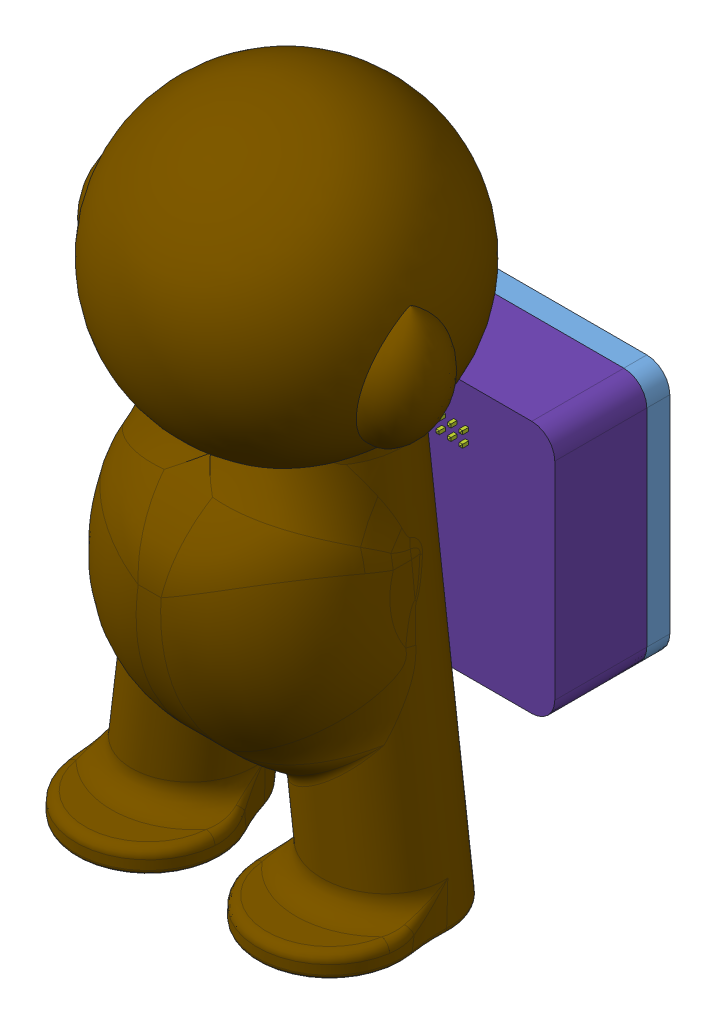
SolidWorks assembly Assieme, configuration Default. Lengths in mm.
Overall size (76.35 143.32 85.77).
234 component instances, 55 part files, 10 mates.
Components (placement in the parent):
- board_assembly v3.step-1: board_assembly v3.step [Default] at (-30.2543 4.1644 104.9326) size (50.34 46.95 25.99)
  - arduino nano.step-1: arduino nano.step [Default] at (25.6471 31.2311 -53.379) x (0 -1 0) z (-1 0 0) size (45 18.6 18)
    - MINIUSB - MEASURED.step-1: MINIUSB - MEASURED.step [Default] at (38.98 1.65 -7.62) x (0 0 1) z (-1 0 0) size (10.9 4.8 10.4)
      - MINIUSBSHELL.step-1: MINIUSBSHELL.step [Default] at origin size (10.9 3.75 9.4)
      - MINIUSBCORE.step-1: MINIUSBCORE.step [Default] at (0 0 6.7) x (-1 0 0) z (0 0 -1) size (7.7 4.5 8.2)
      - MINI USB CONTACT.step-1: MINI USB CONTACT.step [Default] at (-1.6 0 5.7) x (-1 0 0) z (0 0 -1) size (0.51 2.55 9.4)
      - MINI USB CONTACT.step-2: MINI USB CONTACT.step [Default] at (-0.8 0 5.7) x (-1 0 0) z (0 0 -1) size (0.51 2.55 9.4)
      - MINI USB CONTACT.step-3: MINI USB CONTACT.step [Default] at (0 0 5.7) x (-1 0 0) z (0 0 -1) size (0.51 2.55 9.4)
      - MINI USB CONTACT.step-4: MINI USB CONTACT.step [Default] at (0.8 0 5.7) x (-1 0 0) z (0 0 -1) size (0.51 2.55 9.4)
      - MINI USB CONTACT.step-5: MINI USB CONTACT.step [Default] at (1.6 0 5.7) x (-1 0 0) z (0 0 -1) size (0.51 2.55 9.4)
    - reset button.step-1: reset button.step [Default] at (15.25 1.6 -8.05) x (0 0 -1) z (1 0 0) size (5.2 2.15 3)
      - reset core.step-1: reset core.step [Default] at origin size (5.2 2.15 2.8)
      - reset shell.step-1: reset shell.step [Default] at (0 1.65 0) x (0 0 1) z (-1 0 0) size (3 1.65 4)
    - nano-board.step-1: nano-board.step [Default] at origin size (43.2 4.6 18)
    - 2pin_header__02.step-1: 2pin_header__02.step [Default] at (-1.143 1.6 -7.62) size (5 11.75 2.54)
    - 2pin_header__02.step-2: 2pin_header__02.step [Default] at (-1.143 1.6 -5.08) size (5 11.75 2.54)
    - 2pin_header__02.step-3: 2pin_header__02.step [Default] at (-1.143 1.6 -10.16) size (5 11.75 2.54)
    - 15pin_header__.step-1: 15pin_header__.step [Default] x (0 0 1) z (1 0 0) size (2.54 11.75 38.1)
    - 15pin_header__.step-2: 15pin_header__.step [Default] at (0 0 -15.24) x (0 0 1) z (1 0 0) size (2.54 11.75 38.1)
    - atmega328.step-1: atmega328.step [Default] at (23.85 1.75 -7.62) x (-0.707107 0 0.707107) z (-0.707107 0 -0.707107) size (10 1.1 10)
    - ftdi FT232rl.step-1: ftdi FT232rl.step [Default] at (29.05 0 -7.67) x (0 0 -1) z (-1 0 0) size (9.25 1.9 10.2)
    - smt_resistor222.step-1: smt_resistor222.step [Default] at (21.86 0 -5.8) x (0 0 -1) z (-1 0 0) size (1.7 0.6 3.8)
    - smt_resistor222.step-2: smt_resistor222.step [Default] at (21.86 0 -9) x (0 0 -1) z (-1 0 0) size (1.7 0.6 3.8)
    - smt_resistor222.step-3: smt_resistor222.step [Default] at (36.75 0 -7.6) x (0 0 -1) z (-1 0 0) size (1.7 0.6 3.8)
    - smt_resistor222.step-4: smt_resistor222.step [Default] at (36.75 0 -12) x (0 0 -1) z (-1 0 0) size (1.7 0.6 3.8)
    - smt_resistor222.step-5: smt_resistor222.step [Default] at (8.2 0 -2.6) x (0 0 -1) z (-1 0 0) size (1.7 0.6 3.8)
    - led.step-1: led.step [Default] at (10.4 1.6 -2.8) size (4 0.85 1.47)
    - led.step-2: led.step [Default] at (10.4 1.6 -5.55) size (4 0.85 1.47)
    - led.step-3: led.step [Default] at (10.4 1.6 -12.5) size (4 0.85 1.47)
    - led.step-4: led.step [Default] at (10.4 1.6 -9.05) size (4 0.85 1.47)
    - 16mhz crystal - measured.step-1: 16mhz crystal - measured.step [Default] at (18.5113 1.6 -3.5541) x (0.707107 0 0.707107) z (-0.707107 0 0.707107) size (3.4 0.8 2)
    - cap106C.step-1: cap106C.step [Default] at (37.2 0 -3.3) x (0 0 1) z (1 0 0) size (1.7 1.81 4)
    - cap106C.step-2: cap106C.step [Default] at (7.9 0 -5.6) x (0 0 -1) z (-1 0 0) size (1.7 1.81 4)
    - nano - reg.step-1: nano - reg.step [Default] at (6.1 0 -10.16) x (0 0 -1) z (-1 0 0) size (6.5 1.69 8.3)
    - NANO DIODE.step-1: NANO DIODE.step [Default] at (11.43 0 -4.2) x (0 0 1) z (1 0 0) size (4.98 1.45 1.7)
    - 189 RESISTOR PACK.step-1: 189 RESISTOR PACK.step [Default] at (15.75 0 -10.85) x (0 0 1) z (1 0 0) size (3.2 0.46 3)
    - 102 RESISTOR PACK.step-1: 102 RESISTOR PACK.step [Default] at (15.75 0 -5.2) x (0 0 1) z (1 0 0) size (3.2 0.46 3)
  - User Library-MP3-TF-16P.step-1: User Library-MP3-TF-16P.step [Default] at (0 0 -52.7436) size (21.95 22.1 14.38)
    - User Library-MP3-TF-16P_Designator45.step-1: User Library-MP3-TF-16P_Designator45.step [Default] at origin size (1.6 0.86 0.8)
      - User Library-MP3-TF-16P_User_Library-Chip_Capacitor2CAPC0603X33N.step-1: User Library-MP3-TF-16P_User_Library-Chip_Capacitor2CAPC0603X33N.step [Default] at (15.7476 3.0705 -0.7915) x (-1 0 0) z (0 0 -1) size (1.6 0.86 0.8)
    - User Library-MP3-TF-16P_Designator44.step-1: User Library-MP3-TF-16P_Designator44.step [Default] at origin size (1.6 0.86 0.8)
      - User Library-MP3-TF-16P_User_Library-Chip_Capacitor2CAPC0603X33N.step-1: User Library-MP3-TF-16P_User_Library-Chip_Capacitor2CAPC0603X33N.step [Default] at (19.202 3.0705 -0.7915) x (-1 0 0) z (0 0 -1) size (1.6 0.86 0.8)
    - User Library-MP3-TF-16P_Designator43.step-1: User Library-MP3-TF-16P_Designator43.step [Default] at origin size (1.6 0.86 0.8)
      - User Library-MP3-TF-16P_User_Library-Chip_Capacitor2CAPC0603X33N.step-1: User Library-MP3-TF-16P_User_Library-Chip_Capacitor2CAPC0603X33N.step [Default] at (9.042 6.7293 -0.7915) x (-1 0 0) z (0 0 -1) size (1.6 0.86 0.8)
    - User Library-MP3-TF-16P_Designator42.step-1: User Library-MP3-TF-16P_Designator42.step [Default] at origin size (1.6 0.86 0.8)
      - User Library-MP3-TF-16P_User_Library-Chip_Capacitor2CAPC0603X33N.step-1: User Library-MP3-TF-16P_User_Library-Chip_Capacitor2CAPC0603X33N.step [Default] at (9.042 8.4227 -0.7915) x (-1 0 0) z (0 0 -1) size (1.6 0.86 0.8)
    - User Library-MP3-TF-16P_Designator41.step-1: User Library-MP3-TF-16P_Designator41.step [Default] at origin size (1.6 0.86 0.8)
      - User Library-MP3-TF-16P_User_Library-Chip_Capacitor2CAPC0603X33N.step-1: User Library-MP3-TF-16P_User_Library-Chip_Capacitor2CAPC0603X33N.step [Default] at (9.042 13.5027 -0.7915) x (-1 0 0) z (0 0 -1) size (1.6 0.86 0.8)
    - User Library-MP3-TF-16P_Designator40.step-1: User Library-MP3-TF-16P_Designator40.step [Default] at origin size (1.6 0.86 0.8)
      - User Library-MP3-TF-16P_User_Library-Chip_Capacitor2CAPC0603X33N.step-1: User Library-MP3-TF-16P_User_Library-Chip_Capacitor2CAPC0603X33N.step [Default] at (3.073 16.974 -0.7915) x (-1 0 0) z (0 0 -1) size (1.6 0.86 0.8)
    - User Library-MP3-TF-16P_Designator39.step-1: User Library-MP3-TF-16P_Designator39.step [Default] at origin size (1.6 0.86 0.8)
      - User Library-MP3-TF-16P_User_Library-Chip_Capacitor2CAPC0603X33N.step-1: User Library-MP3-TF-16P_User_Library-Chip_Capacitor2CAPC0603X33N.step [Default] at (9.4738 16.974 -0.7915) x (-1 0 0) z (0 0 -1) size (1.6 0.86 0.8)
    - User Library-MP3-TF-16P_Designator38.step-1: User Library-MP3-TF-16P_Designator38.step [Default] at origin size (1.6 0.86 0.8)
      - User Library-MP3-TF-16P_User_Library-Chip_Capacitor2CAPC0603X33N.step-1: User Library-MP3-TF-16P_User_Library-Chip_Capacitor2CAPC0603X33N.step [Default] at (12.6742 16.974 -0.7915) x (-1 0 0) z (0 0 -1) size (1.6 0.86 0.8)
    - User Library-MP3-TF-16P_Designator37.step-1: User Library-MP3-TF-16P_Designator37.step [Default] at origin size (1.6 0.86 0.8)
      - User Library-MP3-TF-16P_User_Library-Chip_Capacitor2CAPC0603X33N.step-1: User Library-MP3-TF-16P_User_Library-Chip_Capacitor2CAPC0603X33N.step [Default] at (19.075 16.974 -0.7915) x (-1 0 0) z (0 0 -1) size (1.6 0.86 0.8)
    - User Library-MP3-TF-16P_Designator27.step-1: User Library-MP3-TF-16P_Designator27.step [Default] at origin size (1.6 0.8 0.4)
      - User Library-MP3-TF-16P_User_Library-res0603-1.step-1: User Library-MP3-TF-16P_User_Library-res0603-1.step [Default] at (12.2682 3.4955 -0.4115) x (1 0 0) z (0 0 -1) size (1.6 0.8 0.4)
    - User Library-MP3-TF-16P_Designator26.step-1: User Library-MP3-TF-16P_Designator26.step [Default] at origin size (1.6 0.8 0.4)
      - User Library-MP3-TF-16P_User_Library-res0603-1.step-1: User Library-MP3-TF-16P_User_Library-res0603-1.step [Default] at (8.8138 3.4955 -0.4115) x (1 0 0) z (0 0 -1) size (1.6 0.8 0.4)
    - User Library-MP3-TF-16P_Designator25.step-1: User Library-MP3-TF-16P_Designator25.step [Default] at origin size (1.6 0.8 0.4)
      - User Library-MP3-TF-16P_User_Library-res0603-1.step-1: User Library-MP3-TF-16P_User_Library-res0603-1.step [Default] at (5.3594 3.4955 -0.4115) x (1 0 0) z (0 0 -1) size (1.6 0.8 0.4)
    - User Library-MP3-TF-16P_Designator24.step-1: User Library-MP3-TF-16P_Designator24.step [Default] at origin size (1.6 0.8 0.4)
      - User Library-MP3-TF-16P_User_Library-res0603-1.step-1: User Library-MP3-TF-16P_User_Library-res0603-1.step [Default] at (1.905 3.4955 -0.4115) x (1 0 0) z (0 0 -1) size (1.6 0.8 0.4)
    - User Library-MP3-TF-16P_Designator23.step-1: User Library-MP3-TF-16P_Designator23.step [Default] at origin size (1.6 0.8 0.4)
      - User Library-MP3-TF-16P_User_Library-res0603-1.step-1: User Library-MP3-TF-16P_User_Library-res0603-1.step [Default] at (9.017 5.461 -0.4115) x (1 0 0) z (0 0 -1) size (1.6 0.8 0.4)
    - User Library-MP3-TF-16P_Designator22.step-1: User Library-MP3-TF-16P_Designator22.step [Default] at origin size (1.6 0.8 0.4)
      - User Library-MP3-TF-16P_User_Library-res0603-1.step-1: User Library-MP3-TF-16P_User_Library-res0603-1.step [Default] at (9.017 10.541 -0.4115) x (1 0 0) z (0 0 -1) size (1.6 0.8 0.4)
    - User Library-MP3-TF-16P_Designator21.step-1: User Library-MP3-TF-16P_Designator21.step [Default] at origin size (1.6 0.8 0.4)
      - User Library-MP3-TF-16P_User_Library-res0603-1.step-1: User Library-MP3-TF-16P_User_Library-res0603-1.step [Default] at (9.017 12.2343 -0.4115) x (1 0 0) z (0 0 -1) size (1.6 0.8 0.4)
    - User Library-MP3-TF-16P_Designator20.step-1: User Library-MP3-TF-16P_Designator20.step [Default] at origin size (1.6 0.8 0.4)
      - User Library-MP3-TF-16P_User_Library-res0603-1.step-1: User Library-MP3-TF-16P_User_Library-res0603-1.step [Default] at (9.017 15.621 -0.4115) x (1 0 0) z (0 0 -1) size (1.6 0.8 0.4)
    - User Library-MP3-TF-16P_Designator19.step-1: User Library-MP3-TF-16P_Designator19.step [Default] at origin size (1.6 0.8 0.4)
      - User Library-MP3-TF-16P_User_Library-res0603-1.step-1: User Library-MP3-TF-16P_User_Library-res0603-1.step [Default] at (6.2484 17.399 -0.4115) x (1 0 0) z (0 0 -1) size (1.6 0.8 0.4)
    - User Library-MP3-TF-16P_Designator18.step-1: User Library-MP3-TF-16P_Designator18.step [Default] at origin size (1.6 0.8 0.4)
      - User Library-MP3-TF-16P_User_Library-res0603-1.step-1: User Library-MP3-TF-16P_User_Library-res0603-1.step [Default] at (15.8496 17.399 -0.4115) x (1 0 0) z (0 0 -1) size (1.6 0.8 0.4)
    - User Library-MP3-TF-16P_Designator17.step-1: User Library-MP3-TF-16P_Designator17.step [Default] at origin size (5 4 1.75)
      - User Library-MP3-TF-16P_1464623456.step-1: User Library-MP3-TF-16P_1464623456.step [Default] at (3.556 10.541 -2.1615) size (5 4 1.75)
        - User Library-MP3-TF-16P_Extruded.step-1: User Library-MP3-TF-16P_Extruded.step [Default] at origin size (5 4 1.75)
    - User Library-MP3-TF-16P_Designator15.step-1: User Library-MP3-TF-16P_Designator15.step [Default] at origin size (8.5 5.4 1.78)
      - User Library-MP3-TF-16P_839474920.step-1: User Library-MP3-TF-16P_839474920.step [Default] at (15.621 10.287 -2.1915) size (8.5 5.4 1.78)
        - User Library-MP3-TF-16P_Extruded_2.step-1: User Library-MP3-TF-16P_Extruded_2.step [Default] at origin size (8.5 5.4 1.78)
    - User Library-MP3-TF-16P_Designator11.step-1: User Library-MP3-TF-16P_Designator11.step [Default] at origin size (1.6 0.86 0.8)
      - User Library-MP3-TF-16P_User_Library-Chip_Capacitor2CAPC0603X33N.step-1: User Library-MP3-TF-16P_User_Library-Chip_Capacitor2CAPC0603X33N.step [Default] at (19.837 4.235 0.38) x (-1 0 0) z (0 0 1) size (1.6 0.86 0.8)
    - User Library-MP3-TF-16P_Designator10.step-1: User Library-MP3-TF-16P_Designator10.step [Default] at origin size (1.6 0.86 0.8)
      - User Library-MP3-TF-16P_User_Library-Chip_Capacitor2CAPC0603X33N.step-1: User Library-MP3-TF-16P_User_Library-Chip_Capacitor2CAPC0603X33N.step [Default] at (19.837 14.522 0.38) x (-1 0 0) z (0 0 1) size (1.6 0.86 0.8)
    - User Library-MP3-TF-16P_Designator9.step-1: User Library-MP3-TF-16P_Designator9.step [Default] at origin size (1.6 0.86 0.8)
      - User Library-MP3-TF-16P_User_Library-Chip_Capacitor2CAPC0603X33N.step-1: User Library-MP3-TF-16P_User_Library-Chip_Capacitor2CAPC0603X33N.step [Default] at (19.837 16.173 0.38) x (-1 0 0) z (0 0 1) size (1.6 0.86 0.8)
    - User Library-MP3-TF-16P_Designator8.step-1: User Library-MP3-TF-16P_Designator8.step [Default] at origin size (1.6 0.86 0.8)
      - User Library-MP3-TF-16P_User_Library-Chip_Capacitor2CAPC0603X33N.step-1: User Library-MP3-TF-16P_User_Library-Chip_Capacitor2CAPC0603X33N.step [Default] at (19.837 17.824 0.38) x (-1 0 0) z (0 0 1) size (1.6 0.86 0.8)
    - User Library-MP3-TF-16P_Designator7.step-1: User Library-MP3-TF-16P_Designator7.step [Default] at origin size (1.6 3.2 1.1)
      - User Library-MP3-TF-16P_User_Library-FYLS-1206.step-1: User Library-MP3-TF-16P_User_Library-FYLS-1206.step [Default] at (18.7229 10.6181 0) x (0 -1 0) z (-1 0 0) size (3.2 1.1 1.6)
    - User Library-MP3-TF-16P_Designator6.step-1: User Library-MP3-TF-16P_Designator6.step [Default] at origin size (1.6 0.8 0.4)
      - User Library-MP3-TF-16P_User_Library-res0603-1.step-1: User Library-MP3-TF-16P_User_Library-res0603-1.step [Default] at (19.812 7.112 0) x (-1 0 0) z (0 0 1) size (1.6 0.8 0.4)
    - User Library-MP3-TF-16P_Designator5.step-1: User Library-MP3-TF-16P_Designator5.step [Default] at origin size (1.6 0.8 0.4)
      - User Library-MP3-TF-16P_User_Library-res0603-1.step-1: User Library-MP3-TF-16P_User_Library-res0603-1.step [Default] at (19.812 5.461 0) x (-1 0 0) z (0 0 1) size (1.6 0.8 0.4)
    - User Library-MP3-TF-16P_Designator4.step-1: User Library-MP3-TF-16P_Designator4.step [Default] at origin size (16.47 19.59 8.41)
      - User Library-MP3-TF-16P_User_Library-MEM2055-00-190-01-A_revG.step-1: User Library-MP3-TF-16P_User_Library-MEM2055-00-190-01-A_revG.step [Default] at (-0.4561 11.7349 0) x (0 -1 0) z (-1 0 0) size (19.59 8.41 16.47)
    - User Library-MP3-TF-16P_Free-Models.step-1: User Library-MP3-TF-16P_Free-Models.step [Default] at origin size (20.32 20.7 11.54)
      - User Library-MP3-TF-16P_65793.step-1: User Library-MP3-TF-16P_65793.step [Default] at (10.541 19.558 -1.8) x (1 0 0) z (0 1 0) size (0.64 11.54 0.64)
      - User Library-MP3-TF-16P_65793.step-2: User Library-MP3-TF-16P_65793.step [Default] at (10.541 1.397 -1.8) x (1 0 0) z (0 1 0) size (0.64 11.54 0.64)
      - User Library-MP3-TF-16P_65793_2.step-1: User Library-MP3-TF-16P_65793_2.step [Default] at (10.541 19.558 -1.8) x (1 0 0) z (0 1 0) size (0.64 11.54 0.64)
      - User Library-MP3-TF-16P_65793_2.step-2: User Library-MP3-TF-16P_65793_2.step [Default] at (10.541 1.397 -1.8) x (1 0 0) z (0 1 0) size (0.64 11.54 0.64)
      - User Library-MP3-TF-16P_65793_3.step-1: User Library-MP3-TF-16P_65793_3.step [Default] at (10.541 1.397 -1.8) x (1 0 0) z (0 1 0) size (0.64 11.54 0.64)
      - User Library-MP3-TF-16P_65793_3.step-2: User Library-MP3-TF-16P_65793_3.step [Default] at (10.541 19.558 -1.8) x (1 0 0) z (0 1 0) size (0.64 11.54 0.64)
      - User Library-MP3-TF-16P_65793_4.step-1: User Library-MP3-TF-16P_65793_4.step [Default] at (10.541 19.558 -1.8) x (1 0 0) z (0 1 0) size (0.64 11.54 0.64)
      - User Library-MP3-TF-16P_65793_4.step-2: User Library-MP3-TF-16P_65793_4.step [Default] at (10.541 1.397 -1.8) x (1 0 0) z (0 1 0) size (0.64 11.54 0.64)
      - User Library-MP3-TF-16P_65793_5.step-1: User Library-MP3-TF-16P_65793_5.step [Default] at (10.541 19.558 -1.8) x (1 0 0) z (0 1 0) size (0.64 11.54 0.64)
      - User Library-MP3-TF-16P_65793_5.step-2: User Library-MP3-TF-16P_65793_5.step [Default] at (10.541 1.397 -1.8) x (1 0 0) z (0 1 0) size (0.64 11.54 0.64)
      - User Library-MP3-TF-16P_65793_6.step-1: User Library-MP3-TF-16P_65793_6.step [Default] at (10.541 19.558 -1.8) x (1 0 0) z (0 1 0) size (0.64 11.54 0.64)
      - User Library-MP3-TF-16P_65793_6.step-2: User Library-MP3-TF-16P_65793_6.step [Default] at (10.541 1.397 -1.8) x (1 0 0) z (0 1 0) size (0.64 11.54 0.64)
      - User Library-MP3-TF-16P_65793_7.step-1: User Library-MP3-TF-16P_65793_7.step [Default] at (10.541 19.558 -1.8) x (1 0 0) z (0 1 0) size (0.64 11.54 0.64)
      - User Library-MP3-TF-16P_65793_7.step-2: User Library-MP3-TF-16P_65793_7.step [Default] at (10.541 1.397 -1.8) x (1 0 0) z (0 1 0) size (0.64 11.54 0.64)
      - User Library-MP3-TF-16P_65793_8.step-1: User Library-MP3-TF-16P_65793_8.step [Default] at (10.541 19.558 -1.8) x (1 0 0) z (0 1 0) size (0.64 11.54 0.64)
      - User Library-MP3-TF-16P_65793_8.step-2: User Library-MP3-TF-16P_65793_8.step [Default] at (10.541 1.397 -1.8) x (1 0 0) z (0 1 0) size (0.64 11.54 0.64)
      - User Library-MP3-TF-16P_65793_9.step-1: User Library-MP3-TF-16P_65793_9.step [Default] at (10.541 19.558 -1.8) x (1 0 0) z (0 1 0) size (20.32 2.54 2.54)
      - User Library-MP3-TF-16P_65793_9.step-2: User Library-MP3-TF-16P_65793_9.step [Default] at (10.541 1.397 -1.8) x (1 0 0) z (0 1 0) size (20.32 2.54 2.54)
    - User Library-MP3-TF-16P_Board.step-1: User Library-MP3-TF-16P_Board.step [Default] at (0 0 -0.4115) size (21.65 21.52 0.43)
  - led_board.step-1: led_board.step [Default] at (47.3811 36.9961 -63.3356) x (-1 0 0) z (0 0 1) size (50 45 15.44)
    - 330R S.step-1: 330R S.step [Default] at (3.9446 14.9766 -1.57) x (1 0 0) z (0 0 -1) size (2 1.25 0.61)
      - Encapsulation.step-1: Encapsulation.step [Default] at (-1.0675 -0.6076 -0.1614) x (1 0 0) z (0 -1 0) size (0.4 0.6 1.25)
      - capsule.step-1: capsule.step [Default] at (-1.0375 -0.6076 -0.1314) x (1 0 0) z (0 -1 0) size (1.94 0.54 1.25)
      - Encapsulation.step-2: Encapsulation.step [Default] at (0.9325 0.6424 -0.1614) x (-1 0 0) z (0 1 0) size (0.4 0.6 1.25)
      - TopCover.step-1: TopCover.step [Default] at (-0.6675 -0.6076 0.4086) x (1 0 0) z (0 -1 0) size (1.2 0.04 1.25)
    - 330R S.step-2: 330R S.step [Default] at (13.1516 6.4036 -1.57) x (1 0 0) z (0 0 -1) size (2 1.25 0.61)
      - Encapsulation.step-1: Encapsulation.step [Default] at (-1.0675 -0.6076 -0.1614) x (1 0 0) z (0 -1 0) size (0.4 0.6 1.25)
      - capsule.step-1: capsule.step [Default] at (-1.0375 -0.6076 -0.1314) x (1 0 0) z (0 -1 0) size (1.94 0.54 1.25)
      - Encapsulation.step-2: Encapsulation.step [Default] at (0.9325 0.6424 -0.1614) x (-1 0 0) z (0 1 0) size (0.4 0.6 1.25)
      - TopCover.step-1: TopCover.step [Default] at (-0.6675 -0.6076 0.4086) x (1 0 0) z (0 -1 0) size (1.2 0.04 1.25)
    - 330R S.step-3: 330R S.step [Default] at (3.9446 17.5166 -1.57) x (1 0 0) z (0 0 -1) size (2 1.25 0.61)
      - Encapsulation.step-1: Encapsulation.step [Default] at (-1.0675 -0.6076 -0.1614) x (1 0 0) z (0 -1 0) size (0.4 0.6 1.25)
      - capsule.step-1: capsule.step [Default] at (-1.0375 -0.6076 -0.1314) x (1 0 0) z (0 -1 0) size (1.94 0.54 1.25)
      - Encapsulation.step-2: Encapsulation.step [Default] at (0.9325 0.6424 -0.1614) x (-1 0 0) z (0 1 0) size (0.4 0.6 1.25)
      - TopCover.step-1: TopCover.step [Default] at (-0.6675 -0.6076 0.4086) x (1 0 0) z (0 -1 0) size (1.2 0.04 1.25)
    - 330R S.step-4: 330R S.step [Default] at (3.9446 27.3586 -1.57) x (1 0 0) z (0 0 -1) size (2 1.25 0.61)
      - Encapsulation.step-1: Encapsulation.step [Default] at (-1.0675 -0.6076 -0.1614) x (1 0 0) z (0 -1 0) size (0.4 0.6 1.25)
      - capsule.step-1: capsule.step [Default] at (-1.0375 -0.6076 -0.1314) x (1 0 0) z (0 -1 0) size (1.94 0.54 1.25)
      - Encapsulation.step-2: Encapsulation.step [Default] at (0.9325 0.6424 -0.1614) x (-1 0 0) z (0 1 0) size (0.4 0.6 1.25)
      - TopCover.step-1: TopCover.step [Default] at (-0.6675 -0.6076 0.4086) x (1 0 0) z (0 -1 0) size (1.2 0.04 1.25)
    - 330R S.step-5: 330R S.step [Default] at (3.9446 29.8986 -1.57) x (1 0 0) z (0 0 -1) size (2 1.25 0.61)
      - Encapsulation.step-1: Encapsulation.step [Default] at (-1.0675 -0.6076 -0.1614) x (1 0 0) z (0 -1 0) size (0.4 0.6 1.25)
      - capsule.step-1: capsule.step [Default] at (-1.0375 -0.6076 -0.1314) x (1 0 0) z (0 -1 0) size (1.94 0.54 1.25)
      - Encapsulation.step-2: Encapsulation.step [Default] at (0.9325 0.6424 -0.1614) x (-1 0 0) z (0 1 0) size (0.4 0.6 1.25)
      - TopCover.step-1: TopCover.step [Default] at (-0.6675 -0.6076 0.4086) x (1 0 0) z (0 -1 0) size (1.2 0.04 1.25)
    - 330R S.step-6: 330R S.step [Default] at (31.8846 1.9586 -1.57) x (-1 0 0) z (0 0 -1) size (2 1.25 0.61)
      - Encapsulation.step-1: Encapsulation.step [Default] at (-1.0675 -0.6076 -0.1614) x (1 0 0) z (0 -1 0) size (0.4 0.6 1.25)
      - capsule.step-1: capsule.step [Default] at (-1.0375 -0.6076 -0.1314) x (1 0 0) z (0 -1 0) size (1.94 0.54 1.25)
      - Encapsulation.step-2: Encapsulation.step [Default] at (0.9325 0.6424 -0.1614) x (-1 0 0) z (0 1 0) size (0.4 0.6 1.25)
      - TopCover.step-1: TopCover.step [Default] at (-0.6675 -0.6076 0.4086) x (1 0 0) z (0 -1 0) size (1.2 0.04 1.25)
    - 330R S.step-7: 330R S.step [Default] at (45.8546 39.1066 -1.57) x (0 -1 0) z (0 0 -1) size (2 1.25 0.61)
      - Encapsulation.step-1: Encapsulation.step [Default] at (-1.0675 -0.6076 -0.1614) x (1 0 0) z (0 -1 0) size (0.4 0.6 1.25)
      - capsule.step-1: capsule.step [Default] at (-1.0375 -0.6076 -0.1314) x (1 0 0) z (0 -1 0) size (1.94 0.54 1.25)
      - Encapsulation.step-2: Encapsulation.step [Default] at (0.9325 0.6424 -0.1614) x (-1 0 0) z (0 1 0) size (0.4 0.6 1.25)
      - TopCover.step-1: TopCover.step [Default] at (-0.6675 -0.6076 0.4086) x (1 0 0) z (0 -1 0) size (1.2 0.04 1.25)
    - 330R S.step-8: 330R S.step [Default] at (13.1516 40.0586 -1.57) x (0 -1 0) z (0 0 -1) size (2 1.25 0.61)
      - Encapsulation.step-1: Encapsulation.step [Default] at (-1.0675 -0.6076 -0.1614) x (1 0 0) z (0 -1 0) size (0.4 0.6 1.25)
      - capsule.step-1: capsule.step [Default] at (-1.0375 -0.6076 -0.1314) x (1 0 0) z (0 -1 0) size (1.94 0.54 1.25)
      - Encapsulation.step-2: Encapsulation.step [Default] at (0.9325 0.6424 -0.1614) x (-1 0 0) z (0 1 0) size (0.4 0.6 1.25)
      - TopCover.step-1: TopCover.step [Default] at (-0.6675 -0.6076 0.4086) x (1 0 0) z (0 -1 0) size (1.2 0.04 1.25)
    - 330R S.step-9: 330R S.step [Default] at (18.8676 40.0586 -1.57) x (0 1 0) z (0 0 -1) size (2 1.25 0.61)
      - Encapsulation.step-1: Encapsulation.step [Default] at (-1.0675 -0.6076 -0.1614) x (1 0 0) z (0 -1 0) size (0.4 0.6 1.25)
      - capsule.step-1: capsule.step [Default] at (-1.0375 -0.6076 -0.1314) x (1 0 0) z (0 -1 0) size (1.94 0.54 1.25)
      - Encapsulation.step-2: Encapsulation.step [Default] at (0.9325 0.6424 -0.1614) x (-1 0 0) z (0 1 0) size (0.4 0.6 1.25)
      - TopCover.step-1: TopCover.step [Default] at (-0.6675 -0.6076 0.4086) x (1 0 0) z (0 -1 0) size (1.2 0.04 1.25)
    - 330R S.step-10: 330R S.step [Default] at (16.0096 40.0586 -1.57) x (0 -1 0) z (0 0 -1) size (2 1.25 0.61)
      - Encapsulation.step-1: Encapsulation.step [Default] at (-1.0675 -0.6076 -0.1614) x (1 0 0) z (0 -1 0) size (0.4 0.6 1.25)
      - capsule.step-1: capsule.step [Default] at (-1.0375 -0.6076 -0.1314) x (1 0 0) z (0 -1 0) size (1.94 0.54 1.25)
      - Encapsulation.step-2: Encapsulation.step [Default] at (0.9325 0.6424 -0.1614) x (-1 0 0) z (0 1 0) size (0.4 0.6 1.25)
      - TopCover.step-1: TopCover.step [Default] at (-0.6675 -0.6076 0.4086) x (1 0 0) z (0 -1 0) size (1.2 0.04 1.25)
    - 330R S.step-11: 330R S.step [Default] at (39.1876 21.3266 -1.57) x (-1 0 0) z (0 0 -1) size (2 1.25 0.61)
      - Encapsulation.step-1: Encapsulation.step [Default] at (-1.0675 -0.6076 -0.1614) x (1 0 0) z (0 -1 0) size (0.4 0.6 1.25)
      - capsule.step-1: capsule.step [Default] at (-1.0375 -0.6076 -0.1314) x (1 0 0) z (0 -1 0) size (1.94 0.54 1.25)
      - Encapsulation.step-2: Encapsulation.step [Default] at (0.9325 0.6424 -0.1614) x (-1 0 0) z (0 1 0) size (0.4 0.6 1.25)
      - TopCover.step-1: TopCover.step [Default] at (-0.6675 -0.6076 0.4086) x (1 0 0) z (0 -1 0) size (1.2 0.04 1.25)
    - 330R S.step-12: 330R S.step [Default] at (39.1876 23.5486 -1.57) x (-1 0 0) z (0 0 -1) size (2 1.25 0.61)
      - Encapsulation.step-1: Encapsulation.step [Default] at (-1.0675 -0.6076 -0.1614) x (1 0 0) z (0 -1 0) size (0.4 0.6 1.25)
      - capsule.step-1: capsule.step [Default] at (-1.0375 -0.6076 -0.1314) x (1 0 0) z (0 -1 0) size (1.94 0.54 1.25)
      - Encapsulation.step-2: Encapsulation.step [Default] at (0.9325 0.6424 -0.1614) x (-1 0 0) z (0 1 0) size (0.4 0.6 1.25)
      - TopCover.step-1: TopCover.step [Default] at (-0.6675 -0.6076 0.4086) x (1 0 0) z (0 -1 0) size (1.2 0.04 1.25)
    - 330R S.step-13: 330R S.step [Default] at (7.1196 13.7066 -1.57) x (0 1 0) z (0 0 -1) size (2 1.25 0.61)
      - Encapsulation.step-1: Encapsulation.step [Default] at (-1.0675 -0.6076 -0.1614) x (1 0 0) z (0 -1 0) size (0.4 0.6 1.25)
      - capsule.step-1: capsule.step [Default] at (-1.0375 -0.6076 -0.1314) x (1 0 0) z (0 -1 0) size (1.94 0.54 1.25)
      - Encapsulation.step-2: Encapsulation.step [Default] at (0.9325 0.6424 -0.1614) x (-1 0 0) z (0 1 0) size (0.4 0.6 1.25)
      - TopCover.step-1: TopCover.step [Default] at (-0.6675 -0.6076 0.4086) x (1 0 0) z (0 -1 0) size (1.2 0.04 1.25)
    - FE08_SMD.step-1: FE08_SMD.step [Default] at (36.9646 35.6136 0) size (20.32 4.57 7.49)
      - _SSM-108-S-SV_body.step-1: _SSM-108-S-SV_body.step [Default] at (0 0 0.156) x (1 0 0) z (0 -1 0) size (20.32 7.37 2.54)
      - _C-95-028.step-1: _C-95-028.step [Default] at (0 0 0.029) x (1 0 0) z (0 -1 0) size (18.29 1.91 4.57)
    - FE08_SMD.step-2: FE08_SMD.step [Default] at (36.9646 17.8336 0) size (20.32 4.57 7.49)
      - _SSM-108-S-SV_body.step-1: _SSM-108-S-SV_body.step [Default] at (0 0 0.156) x (1 0 0) z (0 -1 0) size (20.32 7.37 2.54)
      - _C-95-028.step-1: _C-95-028.step [Default] at (0 0 0.029) x (1 0 0) z (0 -1 0) size (18.29 1.91 4.57)
    - Si2309DS.step-1: Si2309DS.step [Default] at (16.0096 42.5986 0) x (-1 0 0) z (0 0 1) size (3 2.4 1.1)
      - Component1.step-1: Component1.step [Default] at (0 0.05 0) size (3 1.4 1)
      - pin.step-1: pin.step [Default] at (0 0.05 0) size (0.4 0.55 0.6)
      - pin.step-2: pin.step [Default] at (1.9 0.05 0) size (0.4 0.55 0.6)
      - pin.step-3: pin.step [Default] at (-0.95 0.05 0) x (-1 0 0) z (0 0 1) size (0.4 0.55 0.6)
    - FE15_SMD.step-1: FE15_SMD.step [Default] at (6.4846 23.5486 0) x (0 1 0) z (0 0 1) size (38.1 4.57 7.49)
      - _SSM-115-L-SV_body.step-1: _SSM-115-L-SV_body.step [Default] at (-0.0036 -0.0009 0.0906) x (1 0 0) z (0 -1 0) size (38.1 7.37 2.54)
      - _C-95-0215.step-1: _C-95-0215.step [Default] at (-0.0036 -0.0009 -0.0364) x (1 0 0) z (0 -1 0) size (36.07 1.91 4.57)
    - FE15_SMD.step-2: FE15_SMD.step [Default] at (21.7246 23.5486 0) x (0 1 0) z (0 0 1) size (38.1 4.57 7.49)
      - _SSM-115-L-SV_body.step-1: _SSM-115-L-SV_body.step [Default] at (-0.0036 -0.0009 0.0906) x (1 0 0) z (0 -1 0) size (38.1 7.37 2.54)
      - _C-95-0215.step-1: _C-95-0215.step [Default] at (-0.0036 -0.0009 -0.0364) x (1 0 0) z (0 -1 0) size (36.07 1.91 4.57)
    - Board.step-1: Board.step [Default] at (-0.5004 1.9586 0) x (1 0 0) z (0 0 -1) size (50 45 1.57)
    - PHOTOCELLPTH.step-1: PHOTOCELLPTH.step [Default] at (-0.4424 13.0106 -1.57) x (0 1 0) z (0 0 -1) size (4.55 3.8 11.1)
    - PHOTOCELLPTH.step-2: PHOTOCELLPTH.step [Default] at (-0.3754 19.3166 -1.57) x (0 -1 0) z (0 0 -1) size (4.55 3.8 11.1)
    - PHOTOCELLPTH.step-3: PHOTOCELLPTH.step [Default] at (-0.4424 25.5536 -1.57) x (0 1 0) z (0 0 -1) size (4.55 3.8 11.1)
    - PHOTOCELLPTH.step-4: PHOTOCELLPTH.step [Default] at (-0.4924 32.0906 -1.57) x (0 -1 0) z (0 0 -1) size (4.55 3.8 11.1)
    - SMD_SWT.step-1: SMD_SWT.step [Default] at (5.8496 4.1806 -1.57) x (1 0 0) z (0 0 -1) size (10 6 4.4)
    - SMD_SWT.step-2: SMD_SWT.step [Default] at (39.1876 4.1806 -1.57) x (-1 0 0) z (0 0 -1) size (10 6 4.4)
    - SMD_SWT.step-3: SMD_SWT.step [Default] at (39.1876 41.3286 -1.57) x (1 0 0) z (0 0 -1) size (10 6 4.4)
    - SMD_SWT.step-4: SMD_SWT.step [Default] at (6.0196 41.2686 -1.57) x (1 0 0) z (0 0 -1) size (10 6 4.4)
    - 10uF S.step-1: 10uF S.step [Default] at (38.5516 11.1666 -1.57) x (0 1 0) z (0 0 -1) size (2 1.2 1)
    - SMA-DIODE.step-1: SMA-DIODE.step [Default] at (21.7246 41.0106 -1.57) x (0 1 0) z (0 0 -1) size (5.38 2.92 2.46)
    - WS2812B_ALT.step-1: WS2812B_ALT.step [Default] at (11.5646 11.1666 -1.57) x (1 0 0) z (0 0 -1) size (5.35 4.95 1.7)
    - WS2812B_ALT.step-2: WS2812B_ALT.step [Default] at (18.8676 11.1666 -1.57) x (1 0 0) z (0 0 -1) size (5.35 4.95 1.7)
    - WS2812B_ALT.step-3: WS2812B_ALT.step [Default] at (26.1696 11.1666 -1.57) x (1 0 0) z (0 0 -1) size (5.35 4.95 1.7)
    - WS2812B_ALT.step-4: WS2812B_ALT.step [Default] at (33.4716 11.1666 -1.57) x (1 0 0) z (0 0 -1) size (5.35 4.95 1.7)
    - WS2812B_ALT.step-5: WS2812B_ALT.step [Default] at (33.4716 18.4686 -1.57) x (-1 0 0) z (0 0 -1) size (5.35 4.95 1.7)
    - WS2812B_ALT.step-6: WS2812B_ALT.step [Default] at (26.1696 18.4686 -1.57) x (-1 0 0) z (0 0 -1) size (5.35 4.95 1.7)
    - WS2812B_ALT.step-7: WS2812B_ALT.step [Default] at (18.8676 18.4686 -1.57) x (-1 0 0) z (0 0 -1) size (5.35 4.95 1.7)
    - WS2812B_ALT.step-8: WS2812B_ALT.step [Default] at (11.5646 18.4686 -1.57) x (-1 0 0) z (0 0 -1) size (5.35 4.95 1.7)
    - WS2812B_ALT.step-9: WS2812B_ALT.step [Default] at (11.4716 34.3636 -1.57) x (-1 0 0) z (0 0 -1) size (5.35 4.95 1.7)
    - WS2812B_ALT.step-10: WS2812B_ALT.step [Default] at (18.8676 34.3436 -1.57) x (-1 0 0) z (0 0 -1) size (5.35 4.95 1.7)
    - WS2812B_ALT.step-11: WS2812B_ALT.step [Default] at (26.1696 34.3436 -1.57) x (-1 0 0) z (0 0 -1) size (5.35 4.95 1.7)
    - WS2812B_ALT.step-12: WS2812B_ALT.step [Default] at (33.4716 34.3436 -1.57) x (-1 0 0) z (0 0 -1) size (5.35 4.95 1.7)
    - WS2812B_ALT.step-13: WS2812B_ALT.step [Default] at (33.4716 26.4066 -1.57) x (1 0 0) z (0 0 -1) size (5.35 4.95 1.7)
    - WS2812B_ALT.step-14: WS2812B_ALT.step [Default] at (26.1696 26.4066 -1.57) x (1 0 0) z (0 0 -1) size (5.35 4.95 1.7)
    - WS2812B_ALT.step-15: WS2812B_ALT.step [Default] at (18.8676 26.4066 -1.57) x (1 0 0) z (0 0 -1) size (5.35 4.95 1.7)
    - WS2812B_ALT.step-16: WS2812B_ALT.step [Default] at (11.5646 26.4066 -1.57) x (1 0 0) z (0 0 -1) size (5.35 4.95 1.7)
    - BUZZERPTH.step-1: BUZZERPTH.step [Default] at (29.5476 6.2086 0) size (12 12 15)
    - 53047-02.step-1: 53047-02.step [Default] at (46.1716 12.1186 0) x (0 1 0) z (0 0 1) size (1.95 1.4 1)
    - MOLEX_47346-0001.step-1: MOLEX_47346-0001.step [Default] at (30.6146 40.3766 0) x (-1 0 0) z (0 0 1) size (8.2 4.3 1)
- Parte53^Assieme-1: Parte53^Assieme [Default] at (17.6273 39.2019 40.027) x (-1 0 0) z (0 0 -1) size (60 55 20) (virtual)
- Parte54^Assieme-1: Parte54^Assieme [Default] at origin size (76.35 143.32 65) (virtual)
- Parte55^Assieme-1: Parte55^Assieme [Default] at (0 78.6606 0) x (-1 0 0) z (0 -1 0) size (60 5 55) (virtual)
Mates (geometry in assembly coordinates):
- Blocca1: lock: unknown of board_assembly v3.step-1
- SulPosto1: in place: plane of board_assembly v3.step-1/led_board.step-1/Board.step-1 through (-5.3732 18.6606 40.027) normal (0 0 -1); plane of ? through (0 0 40.027) normal (0 0 -1); moOrthogonalPlaneRef_w of board_assembly v3.step-1/led_board.step-1/Board.step-1 through (-5.3732 18.6606 40.027) normal (0 0 -1); plane of ? through (0 0 40.027) normal (0 1 0); plane of board_assembly v3.step-1/led_board.step-1/Board.step-1 through (-5.3732 18.6606 40.027) normal (0 0 -1); plane of ? through (0 0 40.027) normal (-1 0 0); plane of board_assembly v3.step-1/led_board.step-1/Board.step-1 through (-5.3732 18.6606 40.027) normal (0 0 -1); unknown of Parte53^Assieme-1
- Coincidente2: coincident: plane of assembly; plane of assembly; plane of board_assembly v3.step-1/led_board.step-1/Board.step-1; plane of Parte53^Assieme-1
- Coincidente3: coincident: plane of assembly; plane of assembly; moOrthogonalPlaneRef_w of board_assembly v3.step-1/led_board.step-1/Board.step-1 through (17.6273 39.2019 40.027) normal (0 1 0); plane of Parte53^Assieme-1 through (17.6273 39.2019 40.027) normal (0 1 0)
- Coincidente4: coincident: plane of assembly; plane of assembly; moOrthogonalPlaneRef_w of board_assembly v3.step-1/led_board.step-1/Board.step-1 through (17.6273 39.2019 40.027) normal (1 0 0); plane of Parte53^Assieme-1 through (17.6273 39.2019 40.027) normal (-1 0 0)
- Blocca2: lock: unknown of Parte54^Assieme-1
- SulPosto2: in place: plane of Parte54^Assieme-1 through (0 78.6606 0) normal (0 -1 0); plane of Parte55^Assieme-1 through (0 78.6606 0) normal (0 -1 0); plane of Parte54^Assieme-1 through (0 78.6606 0) normal (0 -1 0); plane of Parte55^Assieme-1 through (0 78.6606 0) normal (0 0 -1); plane of Parte54^Assieme-1 through (0 78.6606 0) normal (0 -1 0); plane of Parte55^Assieme-1 through (0 78.6606 0) normal (-1 0 0); plane of Parte54^Assieme-1 through (0 78.6606 0) normal (0 -1 0); unknown of Parte55^Assieme-1
- Coincidente5: coincident: plane of assembly; plane of assembly; plane of Parte54^Assieme-1; plane of Parte55^Assieme-1
- Coincidente6: coincident: plane of assembly; plane of assembly; moOrthogonalPlaneRef_w of Parte54^Assieme-1; plane of Parte55^Assieme-1 through (0 78.6606 0) normal (0 0 -1)
- Coincidente7: coincident: plane of assembly; plane of assembly; moOrthogonalPlaneRef_w of Parte54^Assieme-1; plane of Parte55^Assieme-1 through (0 78.6606 0) normal (-1 0 0)
